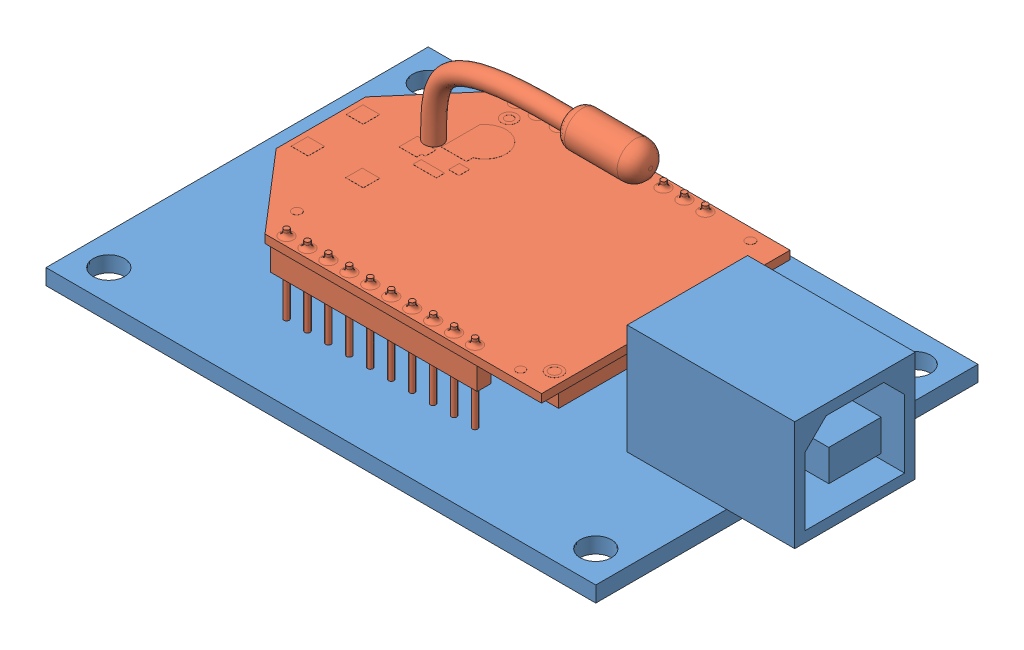
SolidWorks assembly XbeeAss, configuration Default. Lengths in mm.
Overall size (59 18.15 36.5).
2 component instances, 2 part files, 3 mates.
Components (placement in the parent):
- Xbee-1: Xbee [Default] at (-9.0332 27.9523 57.8118) size (59 12 36.5)
- XBeeProS1-1: XBeeProS1 [Default] at (-14.4916 35.5123 57.8118) size (32.94 16.65 23.73)
Mates (geometry in assembly coordinates):
- Coincident1: coincident aligned: plane of Xbee-1 through (-9.0332 29.4523 57.8118) normal (0 1 0); circle of XBeeProS1-1
- Distance1: distance = 8 mm aligned: plane of XBeeProS1-1 through (-27.2832 36.3023 62.0868) normal (-1 0 0); plane of Xbee-1 through (-35.2832 29.4523 39.5618) normal (-1 0 0)
- Width1: width anti-aligned: plane of XBeeProS1-1 through (5.6568 36.3023 69.6768) normal (0 0 1); plane of XBeeProS1-1 through (5.6568 36.3023 45.9468) normal (0 0 -1); plane of Xbee-1 through (-35.2832 29.4523 39.5618) normal (0 0 -1); plane of Xbee-1 through (-35.2832 29.4523 76.0618) normal (0 0 1)
